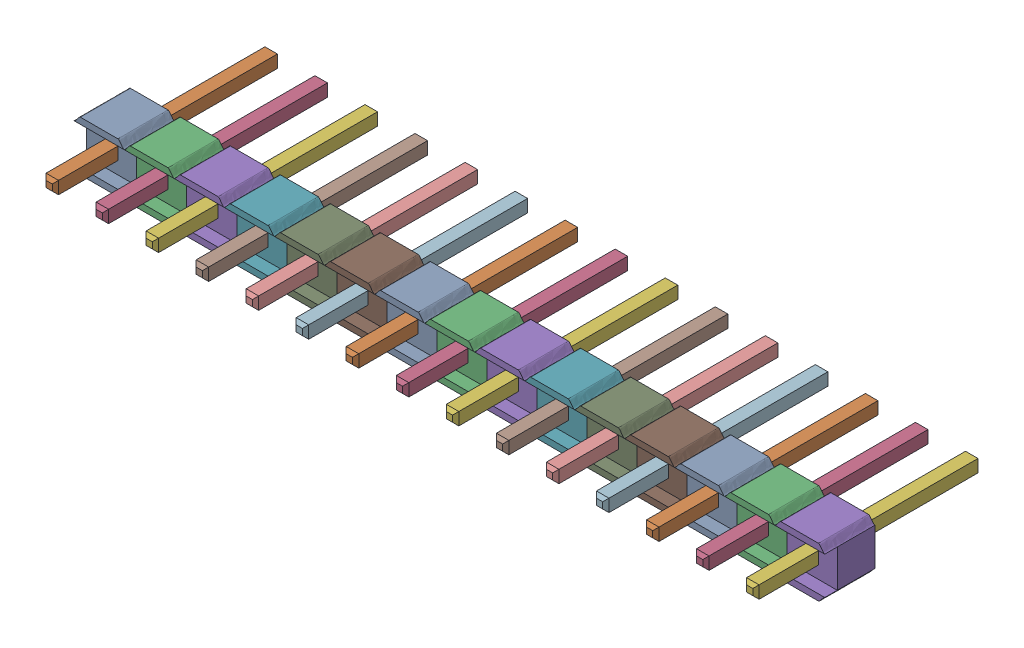
SolidWorks assembly Pin Header 1x15 TH Pitch 2.54mm v3 v1, configuration Default. Lengths in mm.
Overall size (38.1 2.59 11.43).
45 component instances, 2 part files, 0 mates.
Components (placement in the parent):
- asm_pin-1: asm_pin [Default] at (-4.318 1.27 0.0014) x (1 0 0) z (0 0 -1) size (2.54 2.59 11.43)
  - spacer-1: spacer [Default] at origin size (2.54 2.59 2.54)
  - pin-1: pin [Default] at origin size (0.64 0.64 11.43)
- asm_pin_1-1: asm_pin_1 [Default] at (-1.778 1.27 0.0014) x (1 0 0) z (0 0 -1) size (2.54 2.59 11.43)
  - spacer-1: spacer [Default] at origin size (2.54 2.59 2.54)
  - pin-1: pin [Default] at origin size (0.64 0.64 11.43)
- asm_pin_2-1: asm_pin_2 [Default] at (0.762 1.27 0.0014) x (1 0 0) z (0 0 -1) size (2.54 2.59 11.43)
  - spacer-1: spacer [Default] at origin size (2.54 2.59 2.54)
  - pin-1: pin [Default] at origin size (0.64 0.64 11.43)
- asm_pin_3-1: asm_pin_3 [Default] at (3.302 1.27 0.0014) x (1 0 0) z (0 0 -1) size (2.54 2.59 11.43)
  - spacer-1: spacer [Default] at origin size (2.54 2.59 2.54)
  - pin-1: pin [Default] at origin size (0.64 0.64 11.43)
- asm_pin_4-1: asm_pin_4 [Default] at (5.842 1.27 0.0014) x (1 0 0) z (0 0 -1) size (2.54 2.59 11.43)
  - spacer-1: spacer [Default] at origin size (2.54 2.59 2.54)
  - pin-1: pin [Default] at origin size (0.64 0.64 11.43)
- asm_pin_5-1: asm_pin_5 [Default] at (8.382 1.27 0.0014) x (1 0 0) z (0 0 -1) size (2.54 2.59 11.43)
  - spacer-1: spacer [Default] at origin size (2.54 2.59 2.54)
  - pin-1: pin [Default] at origin size (0.64 0.64 11.43)
- asm_pin_6-1: asm_pin_6 [Default] at (10.922 1.27 0.0014) x (1 0 0) z (0 0 -1) size (2.54 2.59 11.43)
  - spacer-1: spacer [Default] at origin size (2.54 2.59 2.54)
  - pin-1: pin [Default] at origin size (0.64 0.64 11.43)
- asm_pin_7-1: asm_pin_7 [Default] at (13.462 1.27 0.0014) x (1 0 0) z (0 0 -1) size (2.54 2.59 11.43)
  - spacer-1: spacer [Default] at origin size (2.54 2.59 2.54)
  - pin-1: pin [Default] at origin size (0.64 0.64 11.43)
- asm_pin_8-1: asm_pin_8 [Default] at (16.002 1.27 0.0014) x (1 0 0) z (0 0 -1) size (2.54 2.59 11.43)
  - spacer-1: spacer [Default] at origin size (2.54 2.59 2.54)
  - pin-1: pin [Default] at origin size (0.64 0.64 11.43)
- asm_pin_9-1: asm_pin_9 [Default] at (18.542 1.27 0.0014) x (1 0 0) z (0 0 -1) size (2.54 2.59 11.43)
  - spacer-1: spacer [Default] at origin size (2.54 2.59 2.54)
  - pin-1: pin [Default] at origin size (0.64 0.64 11.43)
- asm_pin_10-1: asm_pin_10 [Default] at (21.082 1.27 0.0014) x (1 0 0) z (0 0 -1) size (2.54 2.59 11.43)
  - spacer-1: spacer [Default] at origin size (2.54 2.59 2.54)
  - pin-1: pin [Default] at origin size (0.64 0.64 11.43)
- asm_pin_11-1: asm_pin_11 [Default] at (23.622 1.27 0.0014) x (1 0 0) z (0 0 -1) size (2.54 2.59 11.43)
  - spacer-1: spacer [Default] at origin size (2.54 2.59 2.54)
  - pin-1: pin [Default] at origin size (0.64 0.64 11.43)
- asm_pin_12-1: asm_pin_12 [Default] at (26.1619 1.27 0.0014) x (1 0 0) z (0 0 -1) size (2.54 2.59 11.43)
  - spacer-1: spacer [Default] at origin size (2.54 2.59 2.54)
  - pin-1: pin [Default] at origin size (0.64 0.64 11.43)
- asm_pin_13-1: asm_pin_13 [Default] at (28.702 1.27 0.0014) x (1 0 0) z (0 0 -1) size (2.54 2.59 11.43)
  - spacer-1: spacer [Default] at origin size (2.54 2.59 2.54)
  - pin-1: pin [Default] at origin size (0.64 0.64 11.43)
- asm_pin_14-1: asm_pin_14 [Default] at (31.242 1.27 0.0014) x (1 0 0) z (0 0 -1) size (2.54 2.59 11.43)
  - spacer-1: spacer [Default] at origin size (2.54 2.59 2.54)
  - pin-1: pin [Default] at origin size (0.64 0.64 11.43)
